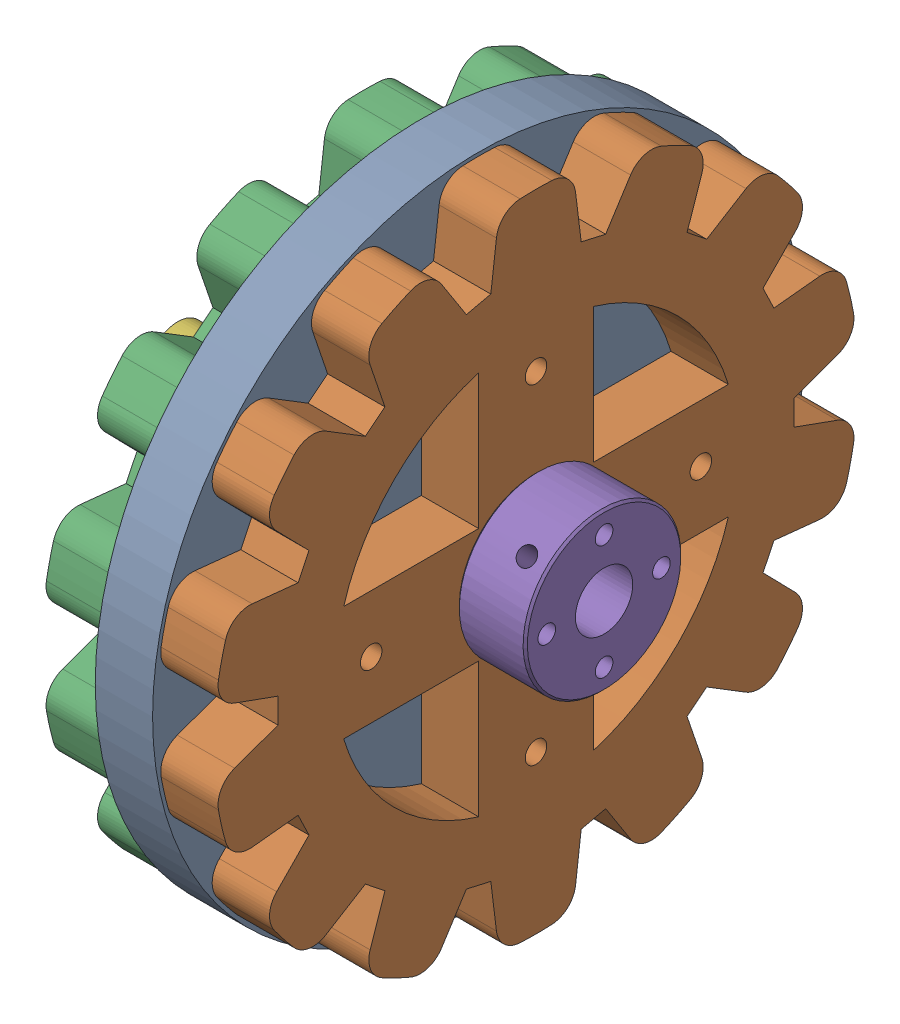
SolidWorks assembly Laser_Sprocket-Dx, configuration Default. Lengths in mm.
Overall size (59.5 91 91).
6 component instances, 4 part files, 14 mates.
Components (placement in the parent):
- Laser-Sprocket_Center-Dx-1: Laser-Sprocket_Center-Dx [Default] at (71.1863 24.8553 -45.995) size (8 91 91)
- Laser-Sprocket_Side-Dx-1: Laser-Sprocket_Side-Dx [Default] at (79.1863 24.8553 -45.995) x (1 0 0) z (0 -1 0) size (8 88.73 90)
- Laser-Sprocket_Side-Dx-2: Laser-Sprocket_Side-Dx [Default] at (63.1863 24.8553 -45.995) x (1 0 0) z (0 -1 0) size (8 88.73 90)
- MotorHub-Dx-1: MotorHub-Dx [Default] at (66.6863 24.8553 -45.995) x (0 1 0) z (0 0 1) size (22 13 22)
- MotorHub-Dx-2: MotorHub-Dx [Default] at (83.6863 24.8553 -45.995) x (0 0 -1) z (0 -1 0) size (22 13 22)
- SprocketShaft-Dx-1: SprocketShaft-Dx [Default] at (37.1863 24.8553 -45.995) x (1 0 0) z (0 0.285041 -0.958515) size (25 8 8)
Mates (geometry in assembly coordinates):
- Concentrico1: concentric aligned: circle of Laser-Sprocket_Side-Dx-1; circle of MotorHub-Dx-2
- Concentrico2: concentric aligned: circle of Laser-Sprocket_Side-Dx-1; circle of MotorHub-Dx-2
- Coincidente1: coincident anti-aligned: plane of Laser-Sprocket_Side-Dx-1 through (87.1863 24.8553 -45.995) normal (1 0 0); plane of MotorHub-Dx-2 through (87.1863 24.8553 -56.995) normal (-1 0 0)
- Concentrico3: concentric aligned: circle of Laser-Sprocket_Center-Dx-1; circle of Laser-Sprocket_Side-Dx-1
- Concentrico4: concentric aligned: circle of Laser-Sprocket_Center-Dx-1; circle of Laser-Sprocket_Side-Dx-1
- Coincidente2: coincident anti-aligned: plane of Laser-Sprocket_Center-Dx-1 through (79.1863 24.8553 -45.995) normal (1 0 0); plane of Laser-Sprocket_Side-Dx-1 through (79.1863 24.8553 -45.995) normal (-1 0 0)
- Concentrico5: concentric aligned: circle of Laser-Sprocket_Center-Dx-1; circle of Laser-Sprocket_Side-Dx-2
- Concentrico6: concentric aligned: circle of Laser-Sprocket_Center-Dx-1; circle of Laser-Sprocket_Side-Dx-2
- Coincidente3: coincident anti-aligned: plane of Laser-Sprocket_Center-Dx-1 through (71.1863 24.8553 -45.995) normal (-1 0 0); plane of Laser-Sprocket_Side-Dx-2 through (71.1863 24.8553 -45.995) normal (1 0 0)
- Concentrico7: concentric anti-aligned: circle of Laser-Sprocket_Side-Dx-2; circle of MotorHub-Dx-1
- Concentrico8: concentric anti-aligned: circle of Laser-Sprocket_Side-Dx-2; circle of MotorHub-Dx-1
- Coincidente4: coincident anti-aligned: plane of Laser-Sprocket_Side-Dx-2 through (63.1863 24.8553 -45.995) normal (-1 0 0); plane of MotorHub-Dx-1 through (63.1863 35.8553 -45.995) normal (1 0 0)
- Concentrico9: concentric anti-aligned: circle of MotorHub-Dx-1; circle of SprocketShaft-Dx-1
- Coincidente5: coincident anti-aligned: plane of MotorHub-Dx-1 through (62.1863 26.8553 -45.995) normal (-1 0 0); plane of SprocketShaft-Dx-1 through (62.1863 24.8553 -45.995) normal (1 0 0)
